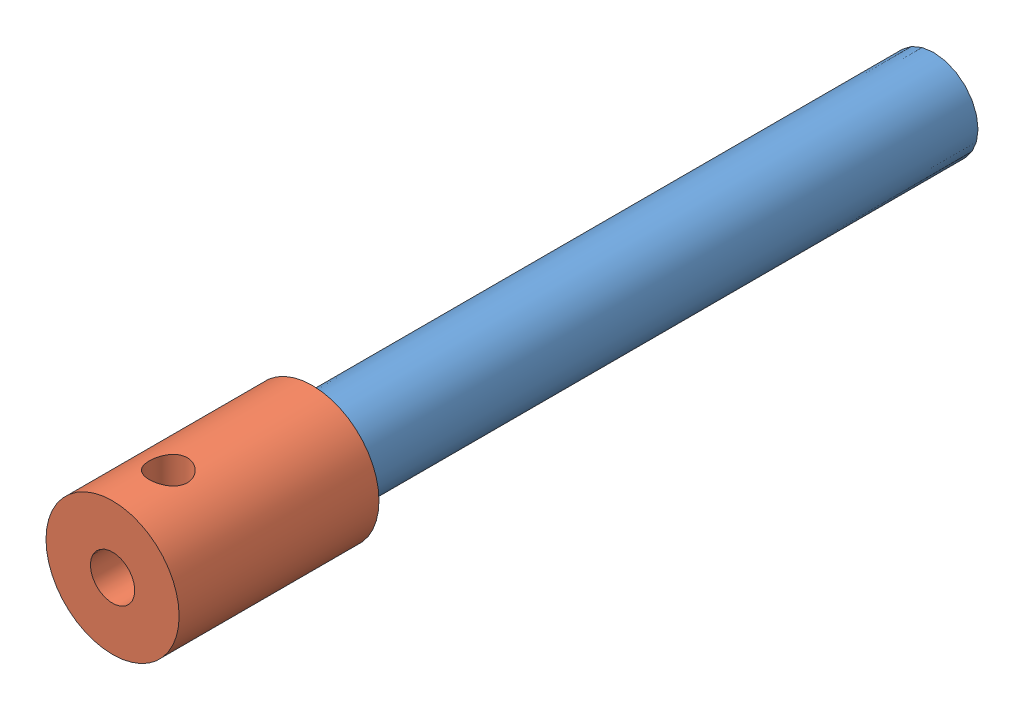
SolidWorks assembly shaft asm, configuration Default. Lengths in mm.
Overall size (9.52 9.52 58.75).
2 component instances, 2 part files, 2 mates.
Components (placement in the parent):
- Shaft Sleeve-1: Shaft Sleeve [Default] at (28.2968 24.2185 10.2246) size (6.35 6.35 50.8)
- Outer Shaft Sleeve-1: Outer Shaft Sleeve [Default] at (28.2968 24.2185 54.6746) size (9.53 9.53 14.3)
Mates (geometry in assembly coordinates):
- Concentric1: concentric: cylinder of Shaft Sleeve-1 through (28.2968 24.2185 61.0246) axis (0 0 -1) radius 3.175; cylinder of Outer Shaft Sleeve-1 through (28.2968 24.2185 61.0246) axis (0 0 -1) radius 3.175
- Coincident1: coincident: plane of Shaft Sleeve-1 through (28.2968 24.2185 61.0246) normal (0 0 1); plane of Outer Shaft Sleeve-1 through (28.2968 24.2185 61.0246) normal (0 0 -1)
